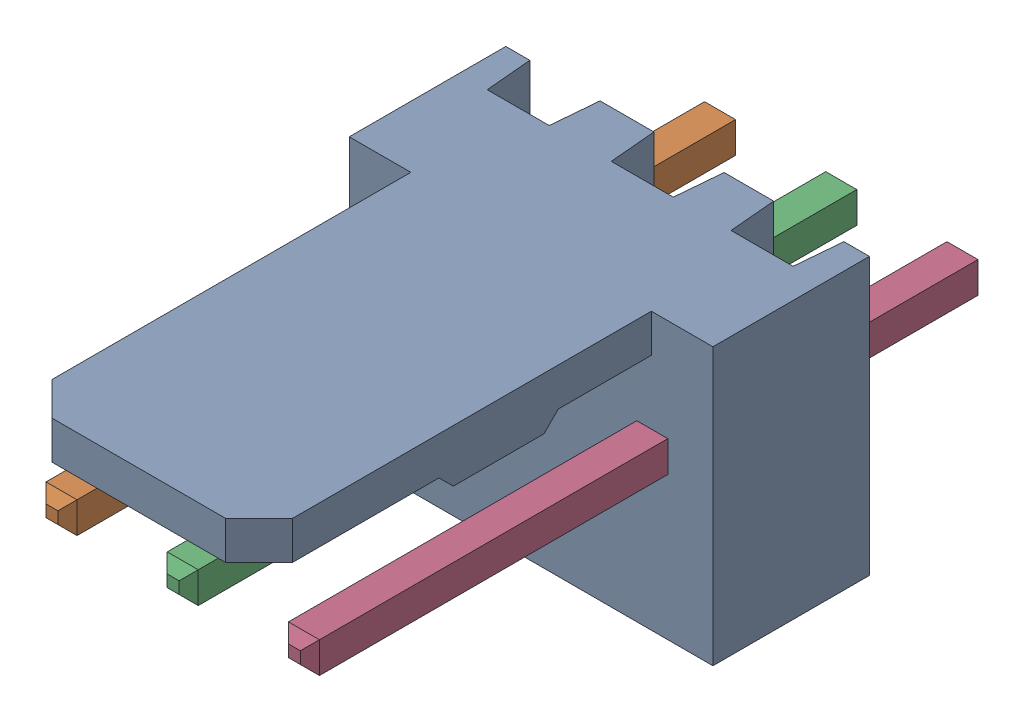
SolidWorks assembly Molex PCB 3 pin v2 v6, configuration Default. Lengths in mm.
Overall size (7.62 5.79 14.92).
4 component instances, 2 part files, 0 mates.
Components (placement in the parent):
- BASE9710016 (1)-1: BASE9710016 (1) [Default] at (2.54 2.895 -8.22) size (7.62 5.79 11.5)
- PINO9710016 (1)-1: PINO9710016 (1) [Default] at (1.27 3.325 -0.72) size (0.65 0.65 14.2)
- PINO9710016 (1)-2: PINO9710016 (1) [Default] at (3.81 3.325 -0.72) size (0.65 0.65 14.2)
- PINO9710016 (1)-3: PINO9710016 (1) [Default] at (6.35 3.325 -0.72) size (0.65 0.65 14.2)
